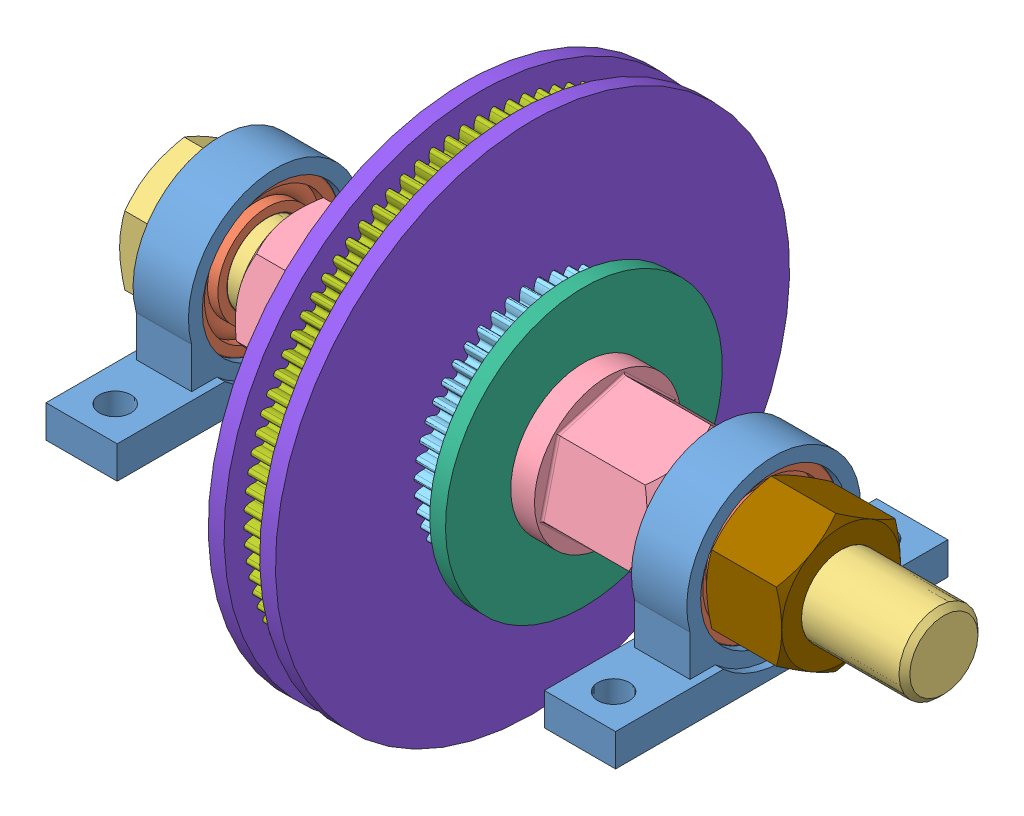
SolidWorks assembly Assem2, configuration Default. Lengths in mm.
Overall size (193.4 130 130).
17 component instances, 9 part files, 24 mates.
Components (placement in the parent):
- Ensamblaje 8M drive assy-1: Ensamblaje 8M drive assy [Predeterminado] at (-73.6027 63.6253 61.5965) x (0 0 -1) z (1 0 0) size (84 46.5 18)
  - fijadores del eje-1: fijadores del eje [Predeterminado] at (36.2208 -24.0928 75) size (84 46.5 18)
  - radial ball bearing_68_skf-3: radial ball bearing_68_skf [SKF - 61904 - 14,SI,NC,14_68] at (-5.7792 0.4072 84.5) x (0 0 1) z (0.143935 -0.989587 0) size (9 37 37)
- hex screw gradec_din-1: hex screw gradec_din [DIN EN 24018 - M20 x 180-WN] at (-7.0027 64.0325 67.3757) size (193.4 34.64 30)
- hex collar nut 1.5d height_din-1: hex collar nut 1.5d height_din [DIN 6331-M20-N] at (22.3973 64.0325 67.3757) x (0 0.293605 0.955927) z (-1 0 0) size (37 37 30)
- hex collar nut 1.5d height_din-2: hex collar nut 1.5d height_din [DIN 6331-M20-N] at (125.3973 64.0325 67.3757) x (0 -0.235551 -0.971862) z (1 0 0) size (37 37 30)
- Polea60-1: Polea60 [Default] at (56.3973 64.0325 67.3757) x (0 0 1) z (0 1 0) size (59.87 9 59.87)
- Protector60-1: Protector60 [Default] at (56.3973 64.0325 67.3757) x (0 1 0) z (0 0 1) size (70 4 70)
- Polea120-1: Polea120 [Default] at (69.3973 64.0325 67.3757) x (0 -0.045827 0.998949) z (0 0.998949 0.045827) size (119.94 9 119.94)
- Protector120-1: Protector120 [Default] at (69.3973 64.0325 67.3757) x (0 0 -1) z (0 1 0) size (130 4 130)
- Protector120-2: Protector120 [Default] at (82.3973 64.0325 67.3757) x (0 0 -1) z (0 1 0) size (130 4 130)
- Polea60-8: Polea60 [Default] at (91.3973 64.0325 67.3757) x (0 -0.969881 0.243579) z (0 -0.243579 -0.969881) size (59.87 9 59.87)
- Protector60-7: Protector60 [Default] at (91.3973 64.0325 67.3757) x (0 0.976285 -0.216491) z (0 -0.216491 -0.976285) size (70 4 70)
- Ensamblaje 8M drive assy-3: Ensamblaje 8M drive assy [Predeterminado] at (52.3973 63.6253 61.5965) x (0 0 -1) z (1 0 0) size (84 46.5 18)
  - fijadores del eje-1: fijadores del eje [Predeterminado] at (36.2208 -24.0928 75) size (84 46.5 18)
  - radial ball bearing_68_skf-3: radial ball bearing_68_skf [SKF - 61904 - 14,SI,NC,14_68] at (-5.7792 0.4072 84.5) x (0 0 1) z (0.143935 -0.989587 0) size (9 37 37)
- hex nut gradec_din-1: hex nut gradec_din [Hexagon Nut ISO 4034 - M20 - N] at (160.3973 64.0325 67.3757) x (0 0 -1) z (1 0 0) size (30 34.64 19)
Mates (geometry in assembly coordinates):
- Concentric1: concentric: cylinder of Ensamblaje 8M drive assy-1/radial ball bearing_68_skf-3 through (-9.7402 64.0325 67.3757) axis (1 0 0) radius 10; cylinder of hex screw gradec_din-1 through (-7.0027 64.0325 67.3757) axis (-1 0 0) radius 10
- Coincident1: coincident: circle of Ensamblaje 8M drive assy-1/radial ball bearing_68_skf-3; plane of hex screw gradec_din-1 through (6.3973 81.353 67.3757) normal (1 0 0)
- Concentric3: concentric: cylinder of hex screw gradec_din-1 through (-7.0027 64.0325 67.3757) axis (-1 0 0) radius 10; cylinder of hex collar nut 1.5d height_din-1 through (52.3973 64.0325 67.3757) axis (-1 0 0) radius 8.75
- Distance1: distance = 7 mm: plane of Ensamblaje 8M drive assy-1/radial ball bearing_68_skf-3 through (15.3973 62.5499 77.5684) normal (1 0 0); plane of hex collar nut 1.5d height_din-1 through (22.3973 55.2243 38.6979) normal (-1 0 0)
- Concentric4: concentric: cylinder of Polea60-1 through (65.3973 64.0325 67.3757) axis (-1 0 0) radius 10; cylinder of Protector60-1 through (62.3973 64.0325 67.3757) axis (-1 0 0) radius 10
- Concentric5: concentric: cylinder of hex screw gradec_din-1 through (-7.0027 64.0325 67.3757) axis (-1 0 0) radius 10; cylinder of Polea60-1 through (65.3973 64.0325 67.3757) axis (-1 0 0) radius 10
- Coincident2: coincident: plane of Polea60-1 through (56.3973 64.0325 67.3757) normal (-1 0 0); plane of Protector60-1 through (56.3973 64.0325 67.3757) normal (1 0 0)
- Coincident3: coincident: plane of hex collar nut 1.5d height_din-1 through (52.3973 55.2243 38.6979) normal (1 0 0); plane of Protector60-1 through (52.3973 64.0325 67.3757) normal (-1 0 0)
- Concentric6: concentric: cylinder of hex screw gradec_din-1 through (-7.0027 64.0325 67.3757) axis (-1 0 0) radius 10; cylinder of Polea120-1 through (78.3973 64.0325 67.3757) axis (-1 0 0) radius 10
- Concentric12: concentric: cylinder of hex screw gradec_din-1 through (-7.0027 64.0325 67.3757) axis (-1 0 0) radius 10; cylinder of Protector120-1 through (75.3973 64.0325 67.3757) axis (-1 0 0) radius 10
- Coincident9: coincident: plane of Polea60-1 through (65.3973 64.0325 67.3757) normal (1 0 0); plane of Protector120-1 through (65.3973 64.0325 67.3757) normal (-1 0 0)
- Coincident10: coincident: plane of Polea120-1 through (69.3973 64.0325 67.3757) normal (-1 0 0); plane of Protector120-1 through (69.3973 64.0325 67.3757) normal (1 0 0)
- Concentric13: concentric: cylinder of hex screw gradec_din-1 through (-7.0027 64.0325 67.3757) axis (-1 0 0) radius 10; cylinder of Protector120-2 through (88.3973 64.0325 67.3757) axis (-1 0 0) radius 10
- Coincident11: coincident: plane of Polea120-1 through (78.3973 64.0325 67.3757) normal (1 0 0); plane of Protector120-2 through (78.3973 64.0325 67.3757) normal (-1 0 0)
- Concentric17: concentric: cylinder of Polea60-8 through (82.3973 64.0325 67.3757) axis (1 0 0) radius 10; cylinder of Protector60-7 through (85.3973 64.0325 67.3757) axis (1 0 0) radius 10
- Coincident15: coincident: plane of Polea60-8 through (91.3973 64.0325 67.3757) normal (1 0 0); plane of Protector60-7 through (91.3973 64.0325 67.3757) normal (-1 0 0)
- Coincident16: coincident: plane of Protector120-2 through (82.3973 64.0325 67.3757) normal (1 0 0); plane of Polea60-8 through (82.3973 64.0325 67.3757) normal (-1 0 0)
- Concentric18: concentric: cylinder of hex screw gradec_din-1 through (-7.0027 64.0325 67.3757) axis (-1 0 0) radius 10; circle of Protector60-7
- Concentric19: concentric: cylinder of hex screw gradec_din-1 through (-7.0027 64.0325 67.3757) axis (-1 0 0) radius 10; cylinder of hex collar nut 1.5d height_din-2 through (95.3973 64.0325 67.3757) axis (1 0 0) radius 8.75
- Coincident17: coincident: plane of hex collar nut 1.5d height_din-2 through (95.3973 71.099 96.5315) normal (-1 0 0); plane of Protector60-7 through (95.3973 64.0325 67.3757) normal (1 0 0)
- Concentric20: concentric: cylinder of hex screw gradec_din-1 through (-7.0027 64.0325 67.3757) axis (-1 0 0) radius 10; cylinder of Ensamblaje 8M drive assy-3/radial ball bearing_68_skf-3 through (116.2598 64.0325 67.3757) axis (1 0 0) radius 10
- Distance3: distance = 7 mm: plane of Ensamblaje 8M drive assy-3/radial ball bearing_68_skf-3 through (132.3973 62.2261 79.795) normal (-1 0 0); plane of hex collar nut 1.5d height_din-2 through (125.3973 71.099 96.5315) normal (1 0 0)
- Concentric21: concentric: cylinder of hex screw gradec_din-1 through (-7.0027 64.0325 67.3757) axis (-1 0 0) radius 10; cylinder of hex nut gradec_din-1 through (141.3973 64.0325 67.3757) axis (1 0 0) radius 8.75
- Coincident18: coincident: plane of Ensamblaje 8M drive assy-3/radial ball bearing_68_skf-3 through (141.3973 62.5499 77.5684) normal (1 0 0); plane of hex nut gradec_din-1 through (141.3973 81.353 67.3757) normal (-1 0 0)
